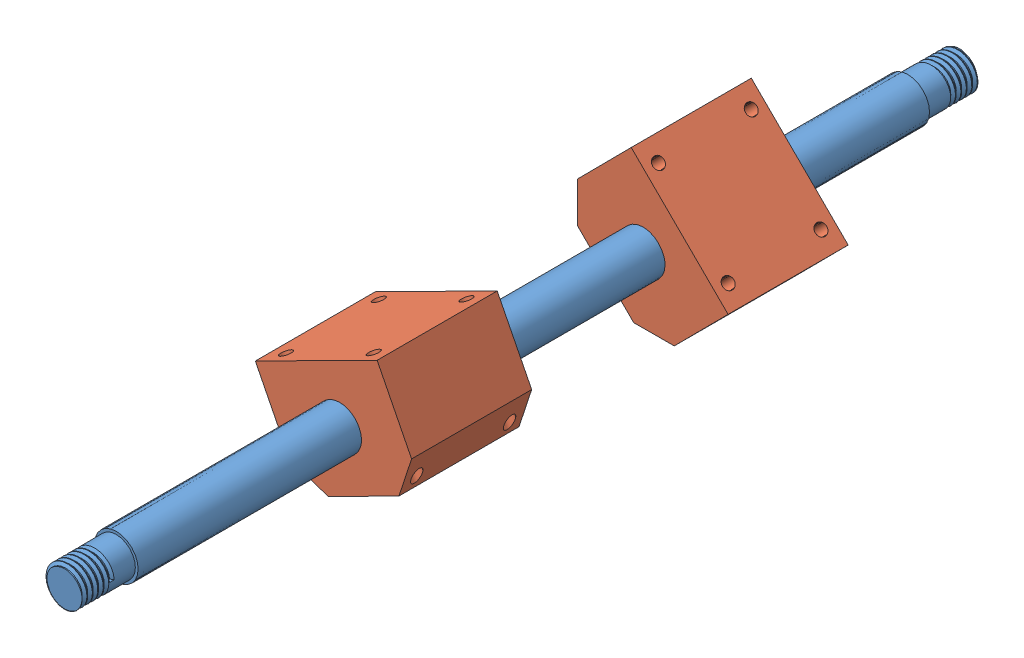
SolidWorks assembly Y slide, configuration Default. Lengths in mm.
Overall size (62.61 62.55 330.39).
3 component instances, 2 part files, 2 mates.
Components (placement in the parent):
- Y rod-1: Y rod [Default] at (118.7688 177.4566 348.0591) size (16 16 330.39)
- sliding block-1: sliding block [Default] at (105.0338 163.6146 182.5284) x (-0.709848 0.704355 0) z (0.704355 0.709848 0) size (50 44 38.5)
- sliding block-2: sliding block [Default] at (127.5609 160.0512 293.749) x (0.892586 0.450878 0) z (-0.450878 0.892586 0) size (50 44 38.5)
Mates (geometry in assembly coordinates):
- Concentric1: concentric aligned: cylinder of Y rod-1 through (118.7688 177.4566 417.0821) axis (0 0 1) radius 8; cylinder of sliding block-1 through (118.7688 177.4566 160.5284) axis (0 0 1) radius 8
- Concentric2: concentric anti-aligned: cylinder of Y rod-1 through (118.7688 177.4566 417.0821) axis (0 0 1) radius 8; cylinder of sliding block-2 through (118.7688 177.4566 315.749) axis (0 0 -1) radius 8
